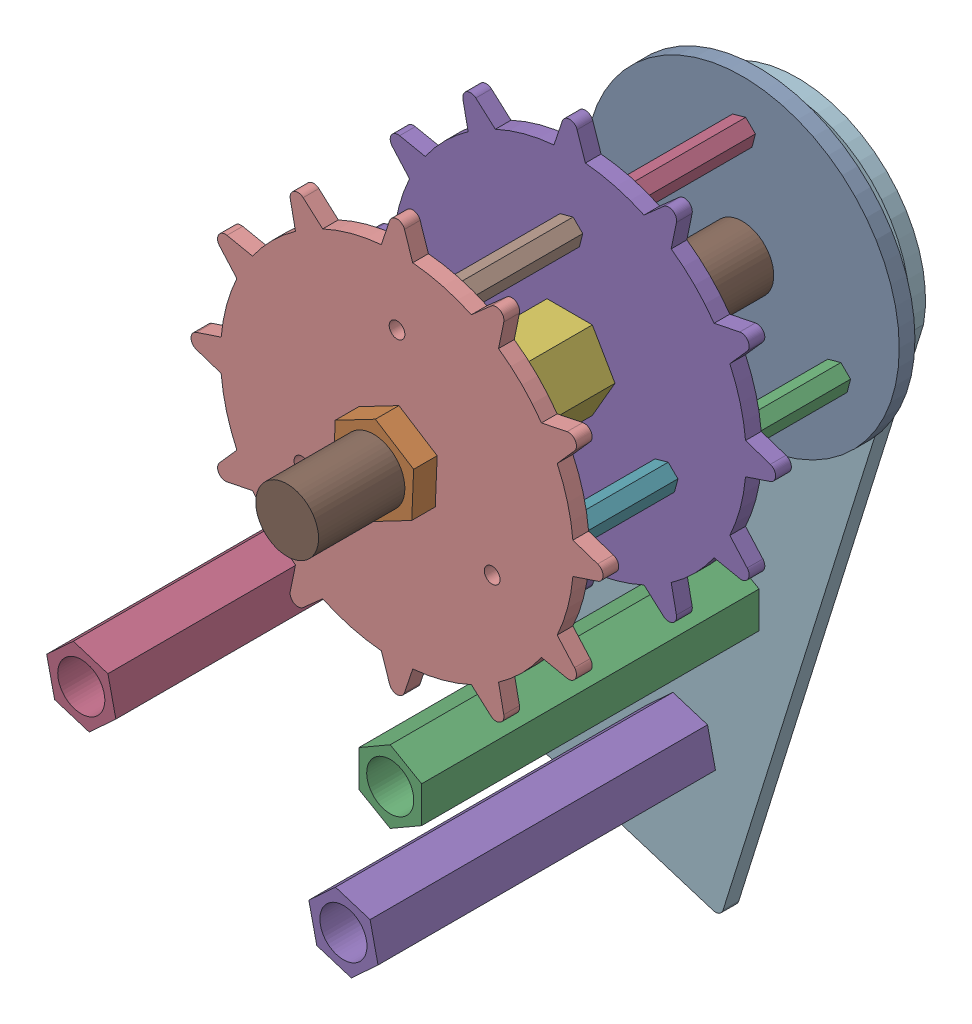
SolidWorks assembly 镜向传动轮, configuration 默认. Lengths in mm.
Overall size (90.9 107.76 70).
17 component instances, 8 part files, 26 mates.
Components (placement in the parent):
- 镜向外侧圆板-1: 镜向外侧圆板 [默认] at (-112.3007 -16.3228 1) size (40 40 2)
- 镜向齿铜柱-1: 镜向齿铜柱 [默认] at (-124.425 -23.3228 21) size (3.34 3.35 20)
- 镜向齿铜柱-2: 镜向齿铜柱 [默认] at (-100.1763 -23.3228 21) x (-0.5 0.866025 0) z (0 0 1) size (3.34 3.35 20)
- 镜向齿铜柱-3: 镜向齿铜柱 [默认] at (-112.3007 -2.3228 21) x (-0.5 -0.866025 0) z (0 0 1) size (3.34 3.35 20)
- 镜向齿-1: 镜向齿 [默认] at (-112.3007 -16.3228 23) size (52.5 52.5 2)
- 镜向齿内测铜柱-1: 镜向齿内测铜柱 [默认] at (-112.3007 -16.3228 43) size (11.55 10 20)
- 镜向齿铜柱-4: 镜向齿铜柱 [默认] at (-100.1763 -23.3228 43) x (-0.5 0.866025 0) z (0 0 1) size (3.34 3.35 20)
- 镜向齿铜柱-5: 镜向齿铜柱 [默认] at (-112.3007 -2.3228 43) x (-0.5 -0.866025 0) z (0 0 1) size (3.34 3.35 20)
- 镜向齿铜柱-6: 镜向齿铜柱 [默认] at (-124.425 -23.3228 43) size (3.34 3.35 20)
- 镜向齿-2: 镜向齿 [默认] at (-112.3007 -16.3228 45) size (52.5 52.5 2)
- 镜向传动轮螺栓-1: 镜向传动轮螺栓 [默认] at (-112.3007 -16.3228 59) x (-0.980386 -0.197089 0) z (0 0 1) size (12.15 13.85 70)
- 镜向最外侧支撑板-1: 镜向最外侧支撑板 [默认] at (-120.0559 -95.5444 -4) x (0.954528 -0.29812 0) z (0 0 1) size (59.6 94.28 2)
- 镜向8M螺母-1: 镜向8M螺母 [默认] at (-112.3007 -16.3228 -1) x (0.96573 0.25955 0) z (0 0 1) size (10.23 11.54 3)
- 镜向8M螺母-2: 镜向8M螺母 [默认] at (-112.3007 -16.3228 48) size (10.23 11.54 3)
- 镜向43铜柱-1: 镜向43铜柱 [默认] at (-119.167 -59.1547 39) x (0.999179 -0.040516 0) z (0 0 1) size (8.18 9.23 43)
- 镜向43铜柱-2: 镜向43铜柱 [默认] at (-158.5379 -67.8111 39) x (-0.336549 -0.941666 0) z (0 0 1) size (8.18 9.23 43)
- 镜向43铜柱-3: 镜向43铜柱 [默认] at (-125.1294 -78.2453 39) x (-0.336549 -0.941666 0) z (0 0 1) size (8.18 9.23 43)
Mates (geometry in assembly coordinates):
- 同心1: concentric: cylinder of assembly; cylinder of assembly; cylinder of 镜向外侧圆板-1 through (-124.425 -23.3228 1) axis (0 0 -1) radius 1; cylinder of 镜向齿铜柱-1 through (-124.425 -23.3228 21) axis (0 0 -1) radius 1
- 重合1: coincident: plane of assembly; plane of assembly; plane of 镜向外侧圆板-1 through (-112.3007 -16.3228 1) normal (0 0 1); plane of 镜向齿铜柱-1 through (-124.425 -23.3228 1) normal (0 0 -1)
- 同心2: concentric: cylinder of assembly; cylinder of assembly; cylinder of 镜向齿铜柱-3 through (-112.3007 -2.3228 21) axis (0 0 -1) radius 1; cylinder of 镜向齿-1 through (-112.3007 -2.3228 23) axis (0 0 -1) radius 1
- 重合2: coincident: plane of assembly; plane of assembly; plane of 镜向齿铜柱-3 through (-112.3007 -2.3228 21) normal (0 0 1); plane of 镜向齿-1 through (-112.3007 -16.3228 21) normal (0 0 -1)
- 同心3: concentric: cylinder of assembly; cylinder of assembly; cylinder of 镜向齿铜柱-2 through (-100.1763 -23.3228 21) axis (0 0 -1) radius 1; cylinder of 镜向齿-1 through (-100.1763 -23.3228 23) axis (0 0 -1) radius 1
- 同心4: concentric: cylinder of assembly; cylinder of assembly; cylinder of 镜向外侧圆板-1 through (-100.1763 -23.3228 1) axis (0 0 -1) radius 1; cylinder of 镜向齿铜柱-2 through (-100.1763 -23.3228 21) axis (0 0 -1) radius 1
- 同心5: concentric: cylinder of assembly; cylinder of assembly; cylinder of 镜向齿-1 through (-112.3007 -16.3228 23) axis (0 0 -1) radius 4; cylinder of 镜向齿内测铜柱-1 through (-112.3007 -16.3228 43) axis (0 0 -1) radius 4
- 重合3: coincident: plane of assembly; plane of assembly; plane of 镜向齿-1 through (-112.3007 -16.3228 23) normal (0 0 1); plane of 镜向齿内测铜柱-1 through (-112.3007 -16.3228 23) normal (0 0 -1)
- 同心6: concentric: cylinder of assembly; cylinder of assembly; cylinder of 镜向齿-1 through (-100.1763 -23.3228 23) axis (0 0 -1) radius 1; cylinder of 镜向齿铜柱-4 through (-100.1763 -23.3228 43) axis (0 0 -1) radius 1
- 重合4: coincident: plane of assembly; plane of assembly; plane of 镜向齿-1 through (-112.3007 -16.3228 23) normal (0 0 1); plane of 镜向齿铜柱-4 through (-100.1763 -23.3228 23) normal (0 0 -1)
- 同心7: concentric: cylinder of assembly; cylinder of assembly; cylinder of 镜向齿铜柱-4 through (-100.1763 -23.3228 43) axis (0 0 -1) radius 1; cylinder of 镜向齿-2 through (-100.1763 -23.3228 45) axis (0 0 -1) radius 1
- 同心8: concentric: cylinder of assembly; cylinder of assembly; cylinder of 镜向齿铜柱-5 through (-112.3007 -2.3228 43) axis (0 0 -1) radius 1; cylinder of 镜向齿-2 through (-112.3007 -2.3228 45) axis (0 0 -1) radius 1
- 重合5: coincident: plane of assembly; plane of assembly; plane of 镜向齿铜柱-5 through (-112.3007 -2.3228 43) normal (0 0 1); plane of 镜向齿-2 through (-112.3007 -16.3228 43) normal (0 0 -1)
- 同心9: concentric: cylinder of assembly; cylinder of assembly; cylinder of 镜向齿内测铜柱-1 through (-112.3007 -16.3228 43) axis (0 0 -1) radius 4; cylinder of 镜向传动轮螺栓-1 through (-112.3007 -16.3228 -6) axis (0 0 1) radius 4
- 重合6: coincident: plane of assembly; plane of assembly; plane of 镜向传动轮螺栓-1 through (-112.3007 -16.3228 -6) normal (0 0 1); plane of 镜向最外侧支撑板-1 through (-120.0559 -95.5444 -6) normal (0 0 -1)
- 同心10: concentric: cylinder of assembly; cylinder of assembly; cylinder of 镜向传动轮螺栓-1 through (-112.3007 -16.3228 -6) axis (0 0 1) radius 4; cylinder of 镜向8M螺母-1 through (-112.3007 -16.3228 -1) axis (0 0 -1) radius 4
- 重合7: coincident: plane of assembly; plane of assembly; plane of 镜向最外侧支撑板-1 through (-120.0559 -95.5444 -4) normal (0 0 1); plane of 镜向8M螺母-1 through (-112.3007 -16.3228 -4) normal (0 0 -1)
- 重合8: coincident: plane of assembly; plane of assembly; plane of 镜向外侧圆板-1 through (-112.3007 -16.3228 -1) normal (0 0 -1); plane of 镜向8M螺母-1 through (-112.3007 -16.3228 -1) normal (0 0 1)
- 同心11: concentric: cylinder of assembly; cylinder of assembly; cylinder of 镜向传动轮螺栓-1 through (-112.3007 -16.3228 -6) axis (0 0 1) radius 4; cylinder of 镜向8M螺母-2 through (-112.3007 -16.3228 48) axis (0 0 -1) radius 4
- 重合9: coincident: plane of assembly; plane of assembly; plane of 镜向齿-2 through (-112.3007 -16.3228 45) normal (0 0 1); plane of 镜向8M螺母-2 through (-112.3007 -16.3228 45) normal (0 0 -1)
- 同心12: concentric: cylinder of assembly; cylinder of assembly; cylinder of 镜向最外侧支撑板-1 through (-119.167 -59.1547 -4) axis (0 0 -1) radius 3; cylinder of 镜向43铜柱-1 through (-119.167 -59.1547 39.001) axis (0 0 -1) radius 3
- 重合10: coincident: plane of assembly; plane of assembly; plane of 镜向最外侧支撑板-1 through (-120.0559 -95.5444 -4) normal (0 0 1); plane of 镜向43铜柱-1 through (-119.167 -59.1547 -4) normal (0 0 -1)
- 同心13: concentric: cylinder of assembly; cylinder of assembly; cylinder of 镜向最外侧支撑板-1 through (-125.1294 -78.2453 -4) axis (0 0 -1) radius 3; cylinder of 镜向43铜柱-3 through (-125.1294 -78.2453 39.001) axis (0 0 -1) radius 3
- 重合11: coincident: plane of assembly; plane of assembly; plane of 镜向最外侧支撑板-1 through (-120.0559 -95.5444 -4) normal (0 0 1); plane of 镜向43铜柱-3 through (-125.1294 -78.2453 -4) normal (0 0 -1)
- 同心14: concentric: cylinder of assembly; cylinder of assembly; cylinder of 镜向最外侧支撑板-1 through (-158.5379 -67.8111 -4) axis (0 0 -1) radius 3; cylinder of 镜向43铜柱-2 through (-158.5379 -67.8111 39.001) axis (0 0 -1) radius 3
- 重合12: coincident: plane of assembly; plane of assembly; plane of 镜向最外侧支撑板-1 through (-120.0559 -95.5444 -4) normal (0 0 1); plane of 镜向43铜柱-2 through (-158.5379 -67.8111 -4) normal (0 0 -1)
